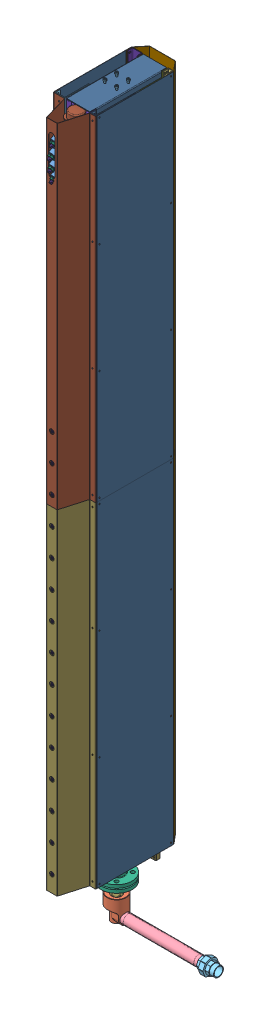
SolidWorks assembly Water Spray Pipe Assembly, configuration Default. Lengths in mm.
Overall size (606.2 3539.3 566.85).
223 component instances, 49 part files, 41 mates.
Components (placement in the parent):
- PPR Water Splitter Assembly – Union Type-1: PPR Water Splitter Assembly – Union Type [Default] at (0 1706.7846 0) x (0 0 1) z (-1 0 0) size (560.85 3301.11 212.13)
  - solenoid_valve_sc_g238c020_3b_oh-1: solenoid_valve_sc_g238c020_3b_oh [Default] at (52.5 414 0) x (-1 0 0) z (0 0 -1) size (140 159.5 110)
    - solenoid_valve_1b_3b_oh-1: solenoid_valve_1b_3b_oh [Default] at origin size (140 159.5 110)
    - solenoid_valve_2b_3b_3b_oh-1: solenoid_valve_2b_3b_3b_oh [Default] at origin size (54 39 30)
    - solenoid_valve_3b_3b_3b_oh-1: solenoid_valve_3b_3b_3b_oh [Default] at (0 212 0) x (1 0 0) z (0 0 -1) size (37.4 51.76 29.51)
  - DN40 Stainless-Steel Water Distributor Assembly-1: DN40 Stainless-Steel Water Distributor Assembly [Default] at origin size (334.07 3215.43 212.13)
    - DN50 PPR water distribution pipe-1: DN50 PPR water distribution pipe [Default] at origin size (244 3175 50)
    - DN50 PPR male-thread union-2: DN50 PPR male-thread union [Default] at (-110.1859 414 0) x (1 0 0) z (0 0.815822 -0.578303) size (73 95.5 95.5)
    - DN50 PPR male-thread union-3: DN50 PPR male-thread union [Default] at (-110.1859 1074 0) x (1 0 0) z (0 0.815822 -0.578303) size (73 95.5 95.5)
    - DN50 PPR male-thread union-4: DN50 PPR male-thread union [Default] at (-110.1859 1734 0) x (1 0 0) z (0 0.815822 -0.578303) size (73 95.5 95.5)
    - DN40-PN25 threaded flange-1: DN40-PN25 threaded flange [Default] at (0 -15 0) x (0 1 0) z (0.707107 0 0.707107) size (34 150 150)
    - DN50 PPR tee-1: DN50 PPR tee [Default] at (-194 414 0) size (85.5 103 68)
    - DN50 PPR female-thread straight connector-1: DN50 PPR female-thread straight connector [Default] at (-142.5 216 0) x (1 0 0) z (0 0.920901 -0.389797) size (67 79.98 79.98)
    - DN50 PPR elbow-1: DN50 PPR elbow [Default] at (-169 241 0) size (85.5 85.5 68)
    - DN50 PPR tee-2: DN50 PPR tee [Default] at (-194 1074 0) size (85.5 103 68)
    - DN50 PPR tee-3: DN50 PPR tee [Default] at (-194 1734 0) size (85.5 103 68)
    - DN50 PPR elbow-2: DN50 PPR elbow [Default] at (-169 3125 0) x (1 0 0) z (0 0 -1) size (85.5 85.5 68)
    - DN50 PPR male-thread union-5: DN50 PPR male-thread union [Default] at (-110.1859 3150 0) x (1 0 0) z (0 0.057891 0.998323) size (73 95.5 95.5)
  - solenoid_valve_sc_g238c020_3b_oh-7: solenoid_valve_sc_g238c020_3b_oh [Default] at (52.5 1074 0) x (-1 0 0) z (0 0 -1) size (140 159.5 110)
    - solenoid_valve_1b_3b_oh-1: solenoid_valve_1b_3b_oh [Default] at origin size (140 159.5 110)
    - solenoid_valve_2b_3b_3b_oh-1: solenoid_valve_2b_3b_3b_oh [Default] at origin size (54 39 30)
    - solenoid_valve_3b_3b_3b_oh-1: solenoid_valve_3b_3b_3b_oh [Default] at (0 212 0) x (1 0 0) z (0 0 -1) size (37.4 51.76 29.51)
  - solenoid_valve_sc_g238c020_3b_oh-8: solenoid_valve_sc_g238c020_3b_oh [Default] at (52.5 1734 0) x (-1 0 0) z (0 0 -1) size (140 159.5 110)
    - solenoid_valve_1b_3b_oh-1: solenoid_valve_1b_3b_oh [Default] at origin size (140 159.5 110)
    - solenoid_valve_2b_3b_3b_oh-1: solenoid_valve_2b_3b_3b_oh [Default] at origin size (54 39 30)
    - solenoid_valve_3b_3b_3b_oh-1: solenoid_valve_3b_3b_3b_oh [Default] at (0 212 0) x (1 0 0) z (0 0 -1) size (37.4 51.76 29.51)
  - solenoid_valve_sc_g238c020_3b_oh-9: solenoid_valve_sc_g238c020_3b_oh [Default] at (52.5 3150 0) x (-1 0 0) z (0 0 -1) size (140 159.5 110)
    - solenoid_valve_1b_3b_oh-1: solenoid_valve_1b_3b_oh [Default] at origin size (140 159.5 110)
    - solenoid_valve_2b_3b_3b_oh-1: solenoid_valve_2b_3b_3b_oh [Default] at origin size (54 39 30)
    - solenoid_valve_3b_3b_3b_oh-1: solenoid_valve_3b_3b_3b_oh [Default] at (0 212 0) x (1 0 0) z (0 0 -1) size (37.4 51.76 29.51)
  - DN50 PPR Distribution Pipe Assembly-1: DN50 PPR Distribution Pipe Assembly [Default] at (194 414 0) x (-1 0 0) z (0 0 -1) size (278.5 642.21 108.73)
    - DN50 PPR tee-1: DN50 PPR tee [Default] at origin size (85.5 103 68)
    - DN50 PPR distributor pipe-1: DN50 PPR distributor pipe [Default] at origin size (50 620 50)
    - DN50 PPR end cap-1: DN50 PPR end cap [Default] at (0 289.2744 0) x (0.993444 0 0.114321) z (-0.114321 0 0.993444) size (66.6 34.61 66.6)
    - DN50 PPR end cap-2: DN50 PPR end cap [Default] at (0 -289.2744 0) x (-0.999521 0 0.030939) z (0.030939 0 0.999521) size (66.6 34.61 66.6)
    - PPR weld in saddle 50–20-1: PPR weld in saddle 50–20 [Default] at (0 132 0) x (0 1 0) z (0 0 1) size (32 32.84 32)
    - PPR weld in saddle 75–20-1: PPR weld in saddle 75–20 [Default] at (3.5 0 0) x (0 1 0) z (0 0 1) size (32 33.38 32)
    - PPR weld in saddle 50–20-5: PPR weld in saddle 50–20 [Default] at (0 264 0) x (0 1 0) z (0 0 1) size (32 32.84 32)
    - DN50 PPR coupling–distributor joint-1: DN50 PPR coupling–distributor joint [Default] at (69 0 0) x (0 0.790854 -0.612005) z (0 0.612005 0.790854) size (50 82 50)
    - DN50 PPR male-thread union-1: DN50 PPR male-thread union [Default] at (118.8141 0 0) x (1 0 0) z (0 -0.1498 -0.988716) size (73 95.5 95.5)
    - PPR weld in saddle 50–20-6: PPR weld in saddle 50–20 [Default] at (0 -264 0) x (0 -1 0) z (0 0 -1) size (32 32.84 32)
    - PPR weld in saddle 50–20-7: PPR weld in saddle 50–20 [Default] at (0 -132 0) x (0 -1 0) z (0 0 -1) size (32 32.84 32)
    - Female Thread Reducer DN15-DN8-1: Female Thread Reducer DN15-DN8 [Default] at (-107.5 -264 0) size (23.99 26.56 23)
    - PPR Female threaded coupling 20xDN15-1: PPR Female threaded coupling 20xDN15 [Default] at (-60.5 -264 0) x (-1 0 0) z (0 -0.051033 -0.998697) size (53.5 35 35)
    - Spay MEG 1530-1: Spay MEG 1530 [Default] at (-98.5 -264 0) x (0 0 1) z (0 -1 0) size (13.5 20.5 15.59)
    - Female Thread Reducer DN15-DN8-2: Female Thread Reducer DN15-DN8 [Default] at (-107.5 -132 0) size (23.99 26.56 23)
    - Female Thread Reducer DN15-DN8-4: Female Thread Reducer DN15-DN8 [Default] at (-107.5 132 0) size (23.99 26.56 23)
    - Female Thread Reducer DN15-DN8-5: Female Thread Reducer DN15-DN8 [Default] at (-107.5 264 0) size (23.99 26.56 23)
    - Spay MEG 1530-2: Spay MEG 1530 [Default] at (-98.5 -132 0) x (0 0 1) z (0 -1 0) size (13.5 20.5 15.59)
    - Spay MEG 1530-4: Spay MEG 1530 [Default] at (-98.5 132 0) x (0 0 1) z (0 -1 0) size (13.5 20.5 15.59)
    - Spay MEG 1530-5: Spay MEG 1530 [Default] at (-98.5 264 0) x (0 0 1) z (0 -1 0) size (13.5 20.5 15.59)
    - PPR Female threaded coupling 20xDN15-2: PPR Female threaded coupling 20xDN15 [Default] at (-60.5 -132 0) x (-1 0 0) z (0 -0.051033 -0.998697) size (53.5 35 35)
    - PPR Female threaded coupling 20xDN15-4: PPR Female threaded coupling 20xDN15 [Default] at (-60.5 132 0) x (-1 0 0) z (0 -0.051033 -0.998697) size (53.5 35 35)
    - PPR Female threaded coupling 20xDN15-5: PPR Female threaded coupling 20xDN15 [Default] at (-60.5 264 0) x (-1 0 0) z (0 -0.051033 -0.998697) size (53.5 35 35)
    - PPR Female threaded coupling 20xDN15-6: PPR Female threaded coupling 20xDN15 [Default] at (-60.5 0 0) x (-1 0 0) z (0 0.107959 -0.994155) size (53.5 35 35)
    - Female Thread Reducer DN15-DN8-6: Female Thread Reducer DN15-DN8 [Default] at (-107.5 0 0) size (23.99 26.56 23)
    - Spay MEG 1530-9: Spay MEG 1530 [Default] at (-98.5 0 0) x (0 0 1) z (0 -1 0) size (13.5 20.5 15.59)
  - DN50 PPR Distribution Pipe Assembly-2: DN50 PPR Distribution Pipe Assembly [Default] at (194 1074 0) x (-1 0 0) z (0 0 -1) size (278.5 642.21 108.73)
    - DN50 PPR tee-1: DN50 PPR tee [Default] at origin size (85.5 103 68)
    - DN50 PPR distributor pipe-1: DN50 PPR distributor pipe [Default] at origin size (50 620 50)
    - DN50 PPR end cap-1: DN50 PPR end cap [Default] at (0 289.2744 0) x (0.993444 0 0.114321) z (-0.114321 0 0.993444) size (66.6 34.61 66.6)
    - DN50 PPR end cap-2: DN50 PPR end cap [Default] at (0 -289.2744 0) x (-0.999521 0 0.030939) z (0.030939 0 0.999521) size (66.6 34.61 66.6)
    - PPR weld in saddle 50–20-1: PPR weld in saddle 50–20 [Default] at (0 132 0) x (0 1 0) z (0 0 1) size (32 32.84 32)
    - PPR weld in saddle 75–20-1: PPR weld in saddle 75–20 [Default] at (3.5 0 0) x (0 1 0) z (0 0 1) size (32 33.38 32)
    - PPR weld in saddle 50–20-5: PPR weld in saddle 50–20 [Default] at (0 264 0) x (0 1 0) z (0 0 1) size (32 32.84 32)
    - DN50 PPR coupling–distributor joint-1: DN50 PPR coupling–distributor joint [Default] at (69 0 0) x (0 0.790854 -0.612005) z (0 0.612005 0.790854) size (50 82 50)
    - DN50 PPR male-thread union-1: DN50 PPR male-thread union [Default] at (118.8141 0 0) x (1 0 0) z (0 -0.1498 -0.988716) size (73 95.5 95.5)
    - PPR weld in saddle 50–20-6: PPR weld in saddle 50–20 [Default] at (0 -264 0) x (0 -1 0) z (0 0 -1) size (32 32.84 32)
    - PPR weld in saddle 50–20-7: PPR weld in saddle 50–20 [Default] at (0 -132 0) x (0 -1 0) z (0 0 -1) size (32 32.84 32)
    - Female Thread Reducer DN15-DN8-1: Female Thread Reducer DN15-DN8 [Default] at (-107.5 -264 0) size (23.99 26.56 23)
    - PPR Female threaded coupling 20xDN15-1: PPR Female threaded coupling 20xDN15 [Default] at (-60.5 -264 0) x (-1 0 0) z (0 -0.051033 -0.998697) size (53.5 35 35)
    - Spay MEG 1530-1: Spay MEG 1530 [Default] at (-98.5 -264 0) x (0 0 1) z (0 -1 0) size (13.5 20.5 15.59)
    - Female Thread Reducer DN15-DN8-2: Female Thread Reducer DN15-DN8 [Default] at (-107.5 -132 0) size (23.99 26.56 23)
    - Female Thread Reducer DN15-DN8-4: Female Thread Reducer DN15-DN8 [Default] at (-107.5 132 0) size (23.99 26.56 23)
    - Female Thread Reducer DN15-DN8-5: Female Thread Reducer DN15-DN8 [Default] at (-107.5 264 0) size (23.99 26.56 23)
    - Spay MEG 1530-2: Spay MEG 1530 [Default] at (-98.5 -132 0) x (0 0 1) z (0 -1 0) size (13.5 20.5 15.59)
    - Spay MEG 1530-4: Spay MEG 1530 [Default] at (-98.5 132 0) x (0 0 1) z (0 -1 0) size (13.5 20.5 15.59)
    - Spay MEG 1530-5: Spay MEG 1530 [Default] at (-98.5 264 0) x (0 0 1) z (0 -1 0) size (13.5 20.5 15.59)
    - PPR Female threaded coupling 20xDN15-2: PPR Female threaded coupling 20xDN15 [Default] at (-60.5 -132 0) x (-1 0 0) z (0 -0.051033 -0.998697) size (53.5 35 35)
    - PPR Female threaded coupling 20xDN15-4: PPR Female threaded coupling 20xDN15 [Default] at (-60.5 132 0) x (-1 0 0) z (0 -0.051033 -0.998697) size (53.5 35 35)
    - PPR Female threaded coupling 20xDN15-5: PPR Female threaded coupling 20xDN15 [Default] at (-60.5 264 0) x (-1 0 0) z (0 -0.051033 -0.998697) size (53.5 35 35)
    - PPR Female threaded coupling 20xDN15-6: PPR Female threaded coupling 20xDN15 [Default] at (-60.5 0 0) x (-1 0 0) z (0 0.107959 -0.994155) size (53.5 35 35)
    - Female Thread Reducer DN15-DN8-6: Female Thread Reducer DN15-DN8 [Default] at (-107.5 0 0) size (23.99 26.56 23)
    - Spay MEG 1530-9: Spay MEG 1530 [Default] at (-98.5 0 0) x (0 0 1) z (0 -1 0) size (13.5 20.5 15.59)
  - DN50 PPR Distribution Pipe Assembly-3: DN50 PPR Distribution Pipe Assembly [Default] at (194 1734 0) x (-1 0 0) z (0 0 -1) size (278.5 642.21 108.73)
    - DN50 PPR tee-1: DN50 PPR tee [Default] at origin size (85.5 103 68)
    - DN50 PPR distributor pipe-1: DN50 PPR distributor pipe [Default] at origin size (50 620 50)
    - DN50 PPR end cap-1: DN50 PPR end cap [Default] at (0 289.2744 0) x (0.993444 0 0.114321) z (-0.114321 0 0.993444) size (66.6 34.61 66.6)
    - DN50 PPR end cap-2: DN50 PPR end cap [Default] at (0 -289.2744 0) x (-0.999521 0 0.030939) z (0.030939 0 0.999521) size (66.6 34.61 66.6)
    - PPR weld in saddle 50–20-1: PPR weld in saddle 50–20 [Default] at (0 132 0) x (0 1 0) z (0 0 1) size (32 32.84 32)
    - PPR weld in saddle 75–20-1: PPR weld in saddle 75–20 [Default] at (3.5 0 0) x (0 1 0) z (0 0 1) size (32 33.38 32)
    - PPR weld in saddle 50–20-5: PPR weld in saddle 50–20 [Default] at (0 264 0) x (0 1 0) z (0 0 1) size (32 32.84 32)
    - DN50 PPR coupling–distributor joint-1: DN50 PPR coupling–distributor joint [Default] at (69 0 0) x (0 0.790854 -0.612005) z (0 0.612005 0.790854) size (50 82 50)
    - DN50 PPR male-thread union-1: DN50 PPR male-thread union [Default] at (118.8141 0 0) x (1 0 0) z (0 -0.1498 -0.988716) size (73 95.5 95.5)
    - PPR weld in saddle 50–20-6: PPR weld in saddle 50–20 [Default] at (0 -264 0) x (0 -1 0) z (0 0 -1) size (32 32.84 32)
    - PPR weld in saddle 50–20-7: PPR weld in saddle 50–20 [Default] at (0 -132 0) x (0 -1 0) z (0 0 -1) size (32 32.84 32)
    - Female Thread Reducer DN15-DN8-1: Female Thread Reducer DN15-DN8 [Default] at (-107.5 -264 0) size (23.99 26.56 23)
    - PPR Female threaded coupling 20xDN15-1: PPR Female threaded coupling 20xDN15 [Default] at (-60.5 -264 0) x (-1 0 0) z (0 -0.051033 -0.998697) size (53.5 35 35)
    - Spay MEG 1530-1: Spay MEG 1530 [Default] at (-98.5 -264 0) x (0 0 1) z (0 -1 0) size (13.5 20.5 15.59)
    - Female Thread Reducer DN15-DN8-2: Female Thread Reducer DN15-DN8 [Default] at (-107.5 -132 0) size (23.99 26.56 23)
    - Female Thread Reducer DN15-DN8-4: Female Thread Reducer DN15-DN8 [Default] at (-107.5 132 0) size (23.99 26.56 23)
    - Female Thread Reducer DN15-DN8-5: Female Thread Reducer DN15-DN8 [Default] at (-107.5 264 0) size (23.99 26.56 23)
    - Spay MEG 1530-2: Spay MEG 1530 [Default] at (-98.5 -132 0) x (0 0 1) z (0 -1 0) size (13.5 20.5 15.59)
    - Spay MEG 1530-4: Spay MEG 1530 [Default] at (-98.5 132 0) x (0 0 1) z (0 -1 0) size (13.5 20.5 15.59)
    - Spay MEG 1530-5: Spay MEG 1530 [Default] at (-98.5 264 0) x (0 0 1) z (0 -1 0) size (13.5 20.5 15.59)
    - PPR Female threaded coupling 20xDN15-2: PPR Female threaded coupling 20xDN15 [Default] at (-60.5 -132 0) x (-1 0 0) z (0 -0.051033 -0.998697) size (53.5 35 35)
    - PPR Female threaded coupling 20xDN15-4: PPR Female threaded coupling 20xDN15 [Default] at (-60.5 132 0) x (-1 0 0) z (0 -0.051033 -0.998697) size (53.5 35 35)
    - PPR Female threaded coupling 20xDN15-5: PPR Female threaded coupling 20xDN15 [Default] at (-60.5 264 0) x (-1 0 0) z (0 -0.051033 -0.998697) size (53.5 35 35)
    - PPR Female threaded coupling 20xDN15-6: PPR Female threaded coupling 20xDN15 [Default] at (-60.5 0 0) x (-1 0 0) z (0 0.107959 -0.994155) size (53.5 35 35)
    - Female Thread Reducer DN15-DN8-6: Female Thread Reducer DN15-DN8 [Default] at (-107.5 0 0) size (23.99 26.56 23)
    - Spay MEG 1530-9: Spay MEG 1530 [Default] at (-98.5 0 0) x (0 0 1) z (0 -1 0) size (13.5 20.5 15.59)
  - DN50 PPR Distribution Pipe Assembly – Upper-1: DN50 PPR Distribution Pipe Assembly – Upper [Default] at (194 3150 0) x (-1 0 0) z (0 0 -1) size (298.35 272.21 108.73)
    - DN50 PPR tee-1: DN50 PPR tee [Default] at origin size (85.5 103 68)
    - upper DN50 PPR distributor-1: upper DN50 PPR distributor [Default] at origin size (50 250 50)
    - DN50 PPR end cap-1: DN50 PPR end cap [Default] at (0 104.2744 0) x (0.993444 0 0.114321) z (-0.114321 0 0.993444) size (66.6 34.61 66.6)
    - DN50 PPR end cap-2: DN50 PPR end cap [Default] at (0 -104.2744 0) x (-0.999521 0 0.030939) z (0.030939 0 0.999521) size (66.6 34.61 66.6)
    - PPR weld in saddle 50–20-1: PPR weld in saddle 50–20 [Default] at (0 75 0) x (0 1 0) z (0 0 1) size (32 32.84 32)
    - DN50 PPR coupling–distributor joint-1: DN50 PPR coupling–distributor joint [Default] at (69 0 0) x (0 0.790854 -0.612005) z (0 0.612005 0.790854) size (50 82 50)
    - DN50 PPR male-thread union-1: DN50 PPR male-thread union [Default] at (118.8141 0 0) x (1 0 0) z (0 -0.1498 -0.988716) size (73 95.5 95.5)
    - PPR weld in saddle 75–20-2: PPR weld in saddle 75–20 [Default] at (3.5 25 0) x (0 1 0) z (0 0 1) size (32 33.38 32)
    - PPR weld in saddle 50–20-8: PPR weld in saddle 50–20 [Default] at (0 -75 0) x (0 -1 0) z (0 0 -1) size (32 32.84 32)
    - PPR weld in saddle 75–20-3: PPR weld in saddle 75–20 [Default] at (3.5 -25 0) x (0 -1 0) z (0 0 -1) size (32 33.38 32)
    - PPR Female threaded coupling 20xDN15 45deg-1: PPR Female threaded coupling 20xDN15 45deg [Default] at (-74.4234 67.25 0) x (-0.866025 -0.5 0) z (0 0 -1) size (84.48 41.16 35)
    - Female Thread Reducer DN15-DN8-1: Female Thread Reducer DN15-DN8 [Default] at (-115.9926 43.25 0) x (0.866025 0.5 0) z (0 0 1) size (23.99 26.56 23)
    - Spay MEG 1530-1: Spay MEG 1530 [Default] at (-108.1984 47.75 0) x (0 0 -1) z (-0.5 0.866025 0) size (13.5 20.5 15.59)
    - PPR Female threaded coupling 20xDN15 45deg-3: PPR Female threaded coupling 20xDN15 45deg [Default] at (-83.4234 17.25 0) x (-0.866025 -0.5 0) z (0 0 -1) size (84.48 41.16 35)
    - Female Thread Reducer DN15-DN8-2: Female Thread Reducer DN15-DN8 [Default] at (-124.9926 -6.75 0) x (0.866025 0.5 0) z (0.112965 -0.195661 0.974143) size (23.99 26.56 23)
    - Spay MEG 1530-2: Spay MEG 1530 [Default] at (-117.1984 -2.25 0) x (0 0 -1) z (-0.5 0.866025 0) size (13.5 20.5 15.59)
    - PPR Female threaded coupling 20xDN15 45deg-4: PPR Female threaded coupling 20xDN15 45deg [Default] at (-83.4234 -32.75 0) x (-0.866025 -0.5 0) z (0 0 -1) size (84.48 41.16 35)
    - Female Thread Reducer DN15-DN8-3: Female Thread Reducer DN15-DN8 [Default] at (-124.9926 -56.75 0) x (0.866025 0.5 0) z (0.225773 -0.391051 0.892247) size (23.99 26.56 23)
    - Spay MEG 1530-3: Spay MEG 1530 [Default] at (-117.1984 -52.25 0) x (0 0 -1) z (-0.5 0.866025 0) size (13.5 20.5 15.59)
    - PPR Female threaded coupling 20xDN15 45deg-5: PPR Female threaded coupling 20xDN15 45deg [Default] at (-74.4234 -82.75 0) x (-0.866025 -0.5 0) z (0 0 -1) size (84.48 41.16 35)
    - Female Thread Reducer DN15-DN8-4: Female Thread Reducer DN15-DN8 [Default] at (-115.9926 -106.75 0) x (0.866025 0.5 0) z (0.316742 -0.548613 0.773756) size (23.99 26.56 23)
    - Spay MEG 1530-4: Spay MEG 1530 [Default] at (-108.1984 -102.25 0) x (0 0 -1) z (-0.5 0.866025 0) size (13.5 20.5 15.59)
- Rotary Flange Joint Assembly-1: Rotary Flange Joint Assembly [Default] at (0 1511.7846 0) x (0 0 -1) z (1 0 0) size (212.13 191.3 597.27)
  - HD40R bod-1: HD40R bod [Default] at (0 114 0) x (-1 0 0) z (0 0 1) size (91.8 116.07 91.8)
  - HD40R base v3-3b-1: HD40R base v3-3b [Default] at (0 109 0) x (0.931312 0 0.364223) z (-0.364223 0 0.931312) size (47.5 57 54.85)
  - DN40-PN25 threaded flange-1: DN40-PN25 threaded flange [Default] at (0 180 0) x (0 -1 0) z (-0.707107 0 0.707107) size (34 150 150)
  - water supply pipe-1: water supply pipe [Default] at (0 27.7 25.9) x (0 0 -1) z (0.848409 0.529341 0) size (400 48.3 48.3)
  - DN40 male-female thread adapter-2: DN40 male-female thread adapter [Default] at (0 27.7 413.2) x (0 0 1) z (0.026555 0.999647 0) size (78 76 76)
- Spray-Pipe Housing Assembly-1: Spray-Pipe Housing Assembly [Default] at (0 1777.7846 0) x (0 0 1) z (-1 0 0) size (418.83 3349 198)
  - spray-pipe housing – base-1: spray-pipe housing – base [Default] at origin size (370 25 120)
  - spray-pipe housing – rear panel-1: spray-pipe housing – rear panel [Default] at (0 3 0) x (-1 0 0) z (0 0 -1) size (28 3220 120)
  - spray-pipe housing – front panel-1: spray-pipe housing – front panel [Default] at (0 3 0) size (28 3220 120)
  - spray-pipe housing – cross bar-1: spray-pipe housing – cross bar [Default] at (0 660.5 0) size (314 25 120)
  - spray-pipe housing – cross bar-2: spray-pipe housing – cross bar [Default] at (0 1320.5 0) size (314 25 120)
  - spray-pipe housing – cross bar-3: spray-pipe housing – cross bar [Default] at (0 1980.5 0) size (314 25 120)
  - spray-pipe housing – cross bar-4: spray-pipe housing – cross bar [Default] at (0 2640.5 0) size (314 25 120)
  - spray-pipe housing – cover-1: spray-pipe housing – cover [Default] at (0 3223 0) size (370 25 120)
  - spray-pipe housing – pipe clamp-1: spray-pipe housing – pipe clamp [Default] at (194 451.5 0) size (63 20 90)
  - spray-pipe housing – pipe clamp-8: spray-pipe housing – pipe clamp [Default] at (194 234.5 0) x (1 0 0) z (0 0 -1) size (63 20 90)
  - spray-pipe housing – pipe clamp-9: spray-pipe housing – pipe clamp [Default] at (194 894.5 0) x (1 0 0) z (0 0 -1) size (63 20 90)
  - spray-pipe housing – pipe clamp-10: spray-pipe housing – pipe clamp [Default] at (194 1554.5 0) x (1 0 0) z (0 0 -1) size (63 20 90)
  - spray-pipe housing – pipe clamp-6: spray-pipe housing – pipe clamp [Default] at (194 1111.5 0) size (63 20 90)
  - spray-pipe housing – pipe clamp-7: spray-pipe housing – pipe clamp [Default] at (194 1771.5 0) size (63 20 90)
  - spray-pipe housing – pipe clamp-18: spray-pipe housing – pipe clamp [Default] at (194 2982.5 0) x (1 0 0) z (0 0 -1) size (63 20 90)
  - spray-pipe housing – pipe clamp-20: spray-pipe housing – pipe clamp [Default] at (194 3175.5 0) size (63 20 90)
  - Top flange-1: Top flange [Default] at (0 3226 0) x (0 0 -1) z (1 0 0) size (98 36 98)
  - foam-nozzle hose clamp-1: foam-nozzle hose clamp [Default] at (-163 -87 0) x (0 0 1) z (-1 0 0) size (58 120 21)
  - spray-pipe housing – main-nozzle locator-1: spray-pipe housing – main-nozzle locator [Default] at (0 53 0) size (314 3 120)
  - socket head cap screw_din-1: socket head cap screw_din [DIN 912 M8 x 20 --- 20N] at (28.2843 3244 28.2843) x (0 -1 0) z (0 0 1) size (28 13 13)
  - socket head cap screw_din-2: socket head cap screw_din [DIN 912 M8 x 20 --- 20N] at (28.2843 3244 -28.2843) x (0 -1 0) z (0 0 1) size (28 13 13)
  - socket head cap screw_din-3: socket head cap screw_din [DIN 912 M8 x 20 --- 20N] at (-28.2843 3244 28.2843) x (0 -1 0) z (0 0 1) size (28 13 13)
  - socket head cap screw_din-4: socket head cap screw_din [DIN 912 M8 x 20 --- 20N] at (-28.2843 3244 -28.2843) x (0 -1 0) z (0 0 1) size (28 13 13)
  - prevailing torque nut thin insert_din-1: prevailing torque nut thin insert_din [DIN EN ISO 10511 - M8 - N] at (28.2843 3219.3 -28.2843) x (1 0 0) z (0 -1 0) size (13 15.01 6.76)
  - prevailing torque nut thin insert_din-2: prevailing torque nut thin insert_din [DIN EN ISO 10511 - M8 - N] at (-28.2843 3219.3 -28.2843) x (1 0 0) z (0 -1 0) size (13 15.01 6.76)
  - prevailing torque nut thin insert_din-3: prevailing torque nut thin insert_din [DIN EN ISO 10511 - M8 - N] at (28.2843 3219.3 28.2843) x (1 0 0) z (0 -1 0) size (13 15.01 6.76)
  - prevailing torque nut thin insert_din-4: prevailing torque nut thin insert_din [DIN EN ISO 10511 - M8 - N] at (-28.2843 3219.3 28.2843) x (1 0 0) z (0 -1 0) size (13 15.01 6.76)
  - rear lower side cover-1: rear lower side cover [Default] at (-188 0 86.5) x (0 0 1) z (-1 0 0) size (50 1613 25)
  - rear upper side cover-1: rear upper side cover [Default] at (-188 1613 86.5) x (0 0 1) z (-1 0 0) size (50 1613 25)
  - front lower side cover - left-2: front lower side cover - left [Default] at (188 0 -74) x (0 0 1) z (-1 0 0) size (25 1613 25)
  - front upper side cover - left-2: front upper side cover - left [Default] at (188 1613 -74) x (0 0 1) z (-1 0 0) size (25 1613 25)
  - rear lower side cover - left-2: rear lower side cover - left [Default] at (-188 0 -74) x (0 0 1) z (-1 0 0) size (25 1613 25)
  - rear upper side cover - left-2: rear upper side cover - left [Default] at (-188 1613 -74) x (0 0 1) z (-1 0 0) size (25 1613 25)
  - front lower side cover-1: front lower side cover [Default] at (188 0 86.5) x (0 0 1) z (-1 0 0) size (50 1613 120)
  - front upper side cover-1: front upper side cover [Default] at (188 1613 86.5) x (0 0 1) z (-1 0 0) size (50 1613 120)
  - Foam Nozzle Cluster Assembly-1: Foam Nozzle Cluster Assembly [Default] at (56.5958 38.2308 85) x (0.866025 0.5 0) z (0 0 -1) size (162.22 74.5 56)
    - foam nozzle-1: foam nozzle [Default] at origin size (162.22 46 29)
    - foam-nozzle clamp-1: foam-nozzle clamp [Default] at (45.5 -35 -20.5) x (0 1 0) z (1 0 0) size (70 20 25)
    - foam-nozzle clamp-2: foam-nozzle clamp [Default] at (45.5 35 20.5) x (0 -1 0) z (1 0 0) size (70 20 25)
    - socket head cap screw_din-1: socket head cap screw_din [DIN 912 M6 x 50 --- 24N] at (45.5 30 29.5) x (0 0 -1) z (1 0 0) size (56 10 10)
    - socket head cap screw_din-2: socket head cap screw_din [DIN 912 M6 x 50 --- 24N] at (45.5 -30 29.5) x (0 0 -1) z (1 0 0) size (56 10 10)
    - prevailing torque nut thin insert_din-1: prevailing torque nut thin insert_din [DIN EN ISO 10511 - M6 - N] at (45.5 30 -23.4) x (0.923728 0.383049 0) z (0 0 -1) size (10 11.55 6)
    - prevailing torque nut thin insert_din-2: prevailing torque nut thin insert_din [DIN EN ISO 10511 - M6 - N] at (45.5 -30 -23.4) x (0.923728 0.383049 0) z (0 0 -1) size (10 11.55 6)
  - Foam Nozzle Cluster Assembly-2: Foam Nozzle Cluster Assembly [Default] at (35.5 1200 85) x (1 0 0) z (0 0 -1) size (162.22 74.5 56)
    - foam nozzle-1: foam nozzle [Default] at origin size (162.22 46 29)
    - foam-nozzle clamp-1: foam-nozzle clamp [Default] at (45.5 -35 -20.5) x (0 1 0) z (1 0 0) size (70 20 25)
    - foam-nozzle clamp-2: foam-nozzle clamp [Default] at (45.5 35 20.5) x (0 -1 0) z (1 0 0) size (70 20 25)
    - socket head cap screw_din-1: socket head cap screw_din [DIN 912 M6 x 50 --- 24N] at (45.5 30 29.5) x (0 0 -1) z (1 0 0) size (56 10 10)
    - socket head cap screw_din-2: socket head cap screw_din [DIN 912 M6 x 50 --- 24N] at (45.5 -30 29.5) x (0 0 -1) z (1 0 0) size (56 10 10)
    - prevailing torque nut thin insert_din-1: prevailing torque nut thin insert_din [DIN EN ISO 10511 - M6 - N] at (45.5 30 -23.4) x (0.923728 0.383049 0) z (0 0 -1) size (10 11.55 6)
    - prevailing torque nut thin insert_din-2: prevailing torque nut thin insert_din [DIN EN ISO 10511 - M6 - N] at (45.5 -30 -23.4) x (0.923728 0.383049 0) z (0 0 -1) size (10 11.55 6)
  - Foam Nozzle Cluster Assembly-3: Foam Nozzle Cluster Assembly [Default] at (35.5 1500 85) x (1 0 0) z (0 0 -1) size (162.22 74.5 56)
    - foam nozzle-1: foam nozzle [Default] at origin size (162.22 46 29)
    - foam-nozzle clamp-1: foam-nozzle clamp [Default] at (45.5 -35 -20.5) x (0 1 0) z (1 0 0) size (70 20 25)
    - foam-nozzle clamp-2: foam-nozzle clamp [Default] at (45.5 35 20.5) x (0 -1 0) z (1 0 0) size (70 20 25)
    - socket head cap screw_din-1: socket head cap screw_din [DIN 912 M6 x 50 --- 24N] at (45.5 30 29.5) x (0 0 -1) z (1 0 0) size (56 10 10)
    - socket head cap screw_din-2: socket head cap screw_din [DIN 912 M6 x 50 --- 24N] at (45.5 -30 29.5) x (0 0 -1) z (1 0 0) size (56 10 10)
    - prevailing torque nut thin insert_din-1: prevailing torque nut thin insert_din [DIN EN ISO 10511 - M6 - N] at (45.5 30 -23.4) x (0.923728 0.383049 0) z (0 0 -1) size (10 11.55 6)
    - prevailing torque nut thin insert_din-2: prevailing torque nut thin insert_din [DIN EN ISO 10511 - M6 - N] at (45.5 -30 -23.4) x (0.923728 0.383049 0) z (0 0 -1) size (10 11.55 6)
  - Foam Nozzle Cluster Assembly-4: Foam Nozzle Cluster Assembly [Default] at (83.145 3135.2468 85) x (0.766044 -0.642788 0) z (0 0 -1) size (162.22 74.5 56)
    - foam nozzle-1: foam nozzle [Default] at origin size (162.22 46 29)
    - foam-nozzle clamp-1: foam-nozzle clamp [Default] at (45.5 -35 -20.5) x (0 1 0) z (1 0 0) size (70 20 25)
    - foam-nozzle clamp-2: foam-nozzle clamp [Default] at (45.5 35 20.5) x (0 -1 0) z (1 0 0) size (70 20 25)
    - socket head cap screw_din-1: socket head cap screw_din [DIN 912 M6 x 50 --- 24N] at (45.5 30 29.5) x (0 0 -1) z (1 0 0) size (56 10 10)
    - socket head cap screw_din-2: socket head cap screw_din [DIN 912 M6 x 50 --- 24N] at (45.5 -30 29.5) x (0 0 -1) z (1 0 0) size (56 10 10)
    - prevailing torque nut thin insert_din-1: prevailing torque nut thin insert_din [DIN EN ISO 10511 - M6 - N] at (45.5 30 -23.4) x (0.923728 0.383049 0) z (0 0 -1) size (10 11.55 6)
    - prevailing torque nut thin insert_din-2: prevailing torque nut thin insert_din [DIN EN ISO 10511 - M6 - N] at (45.5 -30 -23.4) x (0.923728 0.383049 0) z (0 0 -1) size (10 11.55 6)
- U bold-1: U bold [Default] at (0 2250.7846 -196) x (-1 0 0) z (0 -1 0) size (67 75.5 11.55)
- U bold-8: U bold [Default] at (0 1990.7846 -196) x (-1 0 0) z (0 -1 0) size (67 75.5 11.55)
- U bold-9: U bold [Default] at (0 2650.7846 -196) x (-1 0 0) z (0 -1 0) size (67 75.5 11.55)
- U bold-10: U bold [Default] at (0 3310.7846 -196) x (-1 0 0) z (0 -1 0) size (67 75.5 11.55)
- U bold-6: U bold [Default] at (0 2910.7846 -196) x (-1 0 0) z (0 -1 0) size (67 75.5 11.55)
- U bold-7: U bold [Default] at (0 3570.7846 -196) x (-1 0 0) z (0 -1 0) size (67 75.5 11.55)
- U bold-11: U bold [Default] at (0 4796.7846 -196) x (-1 0 0) z (0 -1 0) size (67 75.5 11.55)
- water-spray pipe cover – rear-8: water-spray pipe cover – rear [Default] at (-12.5 1777.7846 -233) x (-1 0 0) z (0 0 -1) size (203 1613 74)
- water-spray pipe cover – rear-9: water-spray pipe cover – rear [Default] at (-12.5 3390.7846 -233) x (-1 0 0) z (0 0 -1) size (203 1613 74)
- water-spray pipe cover – side-15: water-spray pipe cover – side [Default] at (-114 2584.2846 0) x (0 0 1) z (-1 0 0) size (370 1613 1)
- water-spray pipe cover – side-17: water-spray pipe cover – side [Default] at (90 2584.2846 0) x (0 0 1) z (-1 0 0) size (370 1613 1)
- water-spray pipe cover – side-18: water-spray pipe cover – side [Default] at (90 4197.2846 0) x (0 0 1) z (-1 0 0) size (370 1613 1)
- water-spray pipe cover – front-upper (reversed)-1: water-spray pipe cover – front-upper (reversed) [Default] at (0 3390.7846 311.5) size (203 1613 150)
- water-spray pipe cover – front-lower (reversed)-4: water-spray pipe cover – front-lower (reversed) [Default] at (0 1777.7846 311.5) size (203 1613 150)
- water-spray pipe cover – side-19: water-spray pipe cover – side [Default] at (-114 4197.2846 0) x (0 0 1) z (-1 0 0) size (370 1613 1)
Mates (geometry in assembly coordinates):
- Coincident3: coincident aligned: line of PPR Water Splitter Assembly – Union Type-1 through (0 1706.7846 0) axis (0 1 0)
- Coincident6: coincident aligned: plane of PPR Water Splitter Assembly – Union Type-1 through (0 1706.7846 0) normal (-1 0 0); plane of Spray-Pipe Housing Assembly-1 through (0 1777.7846 0) normal (-1 0 0)
- Coincident9: coincident anti-aligned: plane of rap ong chia nuoc ppr - zacco-1/rap ong inox chia nuoc DN40-1/Mat bich DN40-PN25 ren-3b-1 through (0 1691.7846 0) normal (0 -1 0); plane of rap khop noi xoay mat bich - 3b-1/Mat bich DN40-PN25 ren-3b-1 through (0 1691.7846 0) normal (0 1 0)
- Concentric6: concentric anti-aligned: cylinder of rap ong chia nuoc ppr - zacco-1/rap ong inox chia nuoc DN40-1/Mat bich DN40-PN25 ren-3b-1 through (0 1709.7846 0) axis (0 -1 0) radius 75; cylinder of rap khop noi xoay mat bich - 3b-1/Mat bich DN40-PN25 ren-3b-1 through (0 1673.7846 0) axis (0 1 0) radius 75
- Coincident11: coincident aligned: line of PPR Water Splitter Assembly – Union Type-1 through (0 1706.7846 0) axis (0 1 0); line of Spray-Pipe Housing Assembly-1 through (0 1777.7846 0) axis (0 1 0)
- Concentric7: concentric anti-aligned: cone of rap ong chia nuoc ppr - zacco-1/rap ong inox chia nuoc DN40-1/ong chia nuoc DN50 PPR-1 through (0 2120.7846 -148.15) axis (0 0 1); cylinder of rap hop chua ong phun_vStorage-1/hop chua ong phun - mat sau-1 through (0 2120.7846 -156.999) axis (0 0 -1) radius 35
- Coincident16: coincident aligned: plane of Spray-Pipe Housing Assembly-1 through (0 1777.7846 0) normal (0 0 1); plane of assembly through (0 0 0) normal (0 0 1)
- Perpendicular1: perpendicular: plane of rap khop noi xoay mat bich - 3b-1 through (0 1511.7846 0) normal (1 0 0); plane of assembly through (0 0 0) normal (0 0 1)
- Concentric24: concentric aligned: cylinder of rap hop chua ong phun_vStorage-1/hop chua ong phun - mat sau-1 through (28.5 2250.7846 -156.999) axis (0 0 -1) radius 3; cylinder of U bold-1 through (28.5 2250.7846 -153.5) axis (0 0 -1) radius 3
- Coincident36: coincident anti-aligned: plane of rap hop chua ong phun_vStorage-1/hop chua ong phun - mat sau-1 through (57 5000.7846 -157) normal (0 0 1); plane of U bold-1 through (0 2250.7846 -157) normal (0 0 -1)
- Concentric25: concentric anti-aligned: cylinder of rap hop chua ong phun_vStorage-1/hop chua ong phun - mat sau-1 through (-28.5 2250.7846 -156.999) axis (0 0 -1) radius 3; cylinder of U bold-1 through (-28.5 2250.7846 -196) axis (0 0 1) radius 3
- Concentric26: concentric aligned: cylinder of rap hop chua ong phun_vStorage-1/hop chua ong phun - mat sau-1 through (28.5 1990.7846 -156.999) axis (0 0 -1) radius 3; cylinder of U bold-2 through (28.5 1990.7846 -153.5) axis (0 0 -1) radius 3
- Coincident37: coincident anti-aligned: plane of rap hop chua ong phun_vStorage-1/hop chua ong phun - mat sau-1 through (57 5000.7846 -157) normal (0 0 1); plane of U bold-2 through (0 1990.7846 -157) normal (0 0 -1)
- Concentric27: concentric anti-aligned: cylinder of rap hop chua ong phun_vStorage-1/hop chua ong phun - mat sau-1 through (-28.5 1990.7846 -156.999) axis (0 0 -1) radius 3; cylinder of U bold-2 through (-28.5 1990.7846 -196) axis (0 0 1) radius 3
- Concentric28: concentric aligned: cylinder of rap hop chua ong phun_vStorage-1/hop chua ong phun - mat sau-1 through (28.5 4796.7846 -156.999) axis (0 0 -1) radius 3; cylinder of U bold-8 through (28.5 4796.7846 -153.5) axis (0 0 -1) radius 3
- Coincident39: coincident anti-aligned: plane of rap hop chua ong phun_vStorage-1/hop chua ong phun - mat sau-1 through (57 5000.7846 -157) normal (0 0 1); plane of U bold-8 through (0 4796.7846 -157) normal (0 0 -1)
- Concentric29: concentric anti-aligned: cylinder of rap hop chua ong phun_vStorage-1/hop chua ong phun - mat sau-1 through (-28.5 4796.7846 -156.999) axis (0 0 -1) radius 3; cylinder of U bold-8 through (-28.5 4796.7846 -196) axis (0 0 1) radius 3
- Distance22: distance = 1.5 mm anti-aligned: plane of op che ong phun nuoc - truoc duoi v2 nguoc-4 through (-113 3390.7846 189.5) normal (1 0 0); plane of rap hop chua ong phun_vStorage-1/op hong duoi truoc_v3-1 through (-111.5 3390.7846 188) normal (-1 0 0)
- Distance23: distance = 1.5 mm anti-aligned: plane of rap hop chua ong phun_vStorage-1/op hong duoi truoc_v3-1 through (-61.5 3390.7846 188) normal (0 0 1); plane of op che ong phun nuoc - truoc duoi v2 nguoc-4 through (-60 3390.7846 189.5) normal (0 0 -1)
- Coincident86: coincident aligned: plane of rap hop chua ong phun_vStorage-1/op hong duoi truoc_v3-1 through (-66 1777.7846 183.5) normal (0 -1 0); plane of op che ong phun nuoc - truoc duoi v2 nguoc-4 through (-112 1777.7846 190.5) normal (0 -1 0)
- Coincident87: coincident aligned: plane of op che ong phun nuoc - truoc tren v2 nguoc-1 through (-60 5003.7846 190.5) normal (0 0 1); plane of op che ong phun nuoc - truoc duoi v2 nguoc-4 through (-60 3390.7846 190.5) normal (0 0 1)
- Coincident88: coincident aligned: plane of op che ong phun nuoc - truoc tren v2 nguoc-1 through (-114 5003.7846 189.5) normal (-1 0 0); plane of op che ong phun nuoc - truoc duoi v2 nguoc-4 through (-114 3390.7846 189.5) normal (-1 0 0)
- Coincident89: coincident anti-aligned: plane of op che ong phun nuoc - truoc tren v2 nguoc-1 through (-112 3390.7846 190.5) normal (0 -1 0); plane of op che ong phun nuoc - truoc duoi v2 nguoc-4 through (87 3390.7846 188.5) normal (0 1 0)
- Coincident90: coincident anti-aligned: plane of op che ong phun nuoc - hong-17 through (89 2584.2846 0) normal (-1 0 0); plane of op che ong phun nuoc - truoc duoi v2 nguoc-4 through (89 3390.7846 189.5) normal (1 0 0)
- Concentric65: concentric anti-aligned: cylinder of op che ong phun nuoc - hong-17 through (90.001 1790.7846 172.5) axis (-1 0 0) radius 3.25; cylinder of op che ong phun nuoc - truoc duoi v2 nguoc-4 through (-123.1924 1790.7846 172.5) axis (1 0 0) radius 3.25
- Concentric66: concentric anti-aligned: cylinder of op che ong phun nuoc - hong-17 through (90.001 2319.7846 172.5) axis (-1 0 0) radius 3.25; cylinder of op che ong phun nuoc - truoc duoi v2 nguoc-4 through (-123.1924 2319.7846 172.5) axis (1 0 0) radius 3.25
- Distance24: distance = 1.5 mm anti-aligned: plane of op che ong phun nuoc - sau v2-8 through (-113 3390.7846 -187) normal (1 0 0); plane of rap hop chua ong phun_vStorage-1/op hong duoi sau-1 through (-111.5 3390.7846 -188) normal (-1 0 0)
- Concentric67: concentric anti-aligned: cylinder of rap hop chua ong phun_vStorage-1/op hong duoi sau-1 through (-111.501 3377.7846 -172.5) axis (1 0 0) radius 4.5; cylinder of op che ong phun nuoc - sau v2-8 through (98.1924 3377.7846 -172.5) axis (-1 0 0) radius 3.25
- Concentric68: concentric anti-aligned: cylinder of rap hop chua ong phun_vStorage-1/op hong duoi sau-1 through (-111.501 2848.7846 -172.5) axis (1 0 0) radius 4.5; cylinder of op che ong phun nuoc - sau v2-8 through (98.1924 2848.7846 -172.5) axis (-1 0 0) radius 3.25
- Coincident92: coincident aligned: plane of op che ong phun nuoc - sau v2-8 through (50.1675 3390.7846 -233.6428) normal (0.766044 0 -0.642788); plane of op che ong phun nuoc - sau v2-9 through (50.1675 5003.7846 -233.6428) normal (0.766044 0 -0.642788)
- Coincident94: coincident anti-aligned: plane of op che ong phun nuoc - sau v2-8 through (89 3390.7846 -186.636) normal (0 1 0); plane of op che ong phun nuoc - sau v2-9 through (48.9351 3390.7846 -234) normal (0 -1 0)
- Coincident95: coincident aligned: plane of op che ong phun nuoc - sau v2-8 through (-75.1675 3390.7846 -233.6428) normal (-0.766044 0 -0.642788); plane of op che ong phun nuoc - sau v2-9 through (-75.1675 5003.7846 -233.6428) normal (-0.766044 0 -0.642788)
- Coincident96: coincident anti-aligned: plane of op che ong phun nuoc - hong-18 through (89 4197.2846 0) normal (-1 0 0); plane of op che ong phun nuoc - truoc tren v2 nguoc-1 through (89 5003.7846 189.5) normal (1 0 0)
- Concentric69: concentric aligned: circle of op che ong phun nuoc - hong-18; circle of op che ong phun nuoc - truoc tren v2 nguoc-1
- Concentric70: concentric anti-aligned: cylinder of op che ong phun nuoc - hong-18 through (90.001 3932.7846 172.5) axis (-1 0 0) radius 3.25; cylinder of op che ong phun nuoc - truoc tren v2 nguoc-1 through (-123.1924 3932.7846 172.5) axis (1 0 0) radius 3.25
- Coincident98: coincident anti-aligned: plane of op che ong phun nuoc - hong-15 through (-114 2584.2846 0) normal (1 0 0); plane of op che ong phun nuoc - truoc duoi v2 nguoc-4 through (-114 3390.7846 189.5) normal (-1 0 0)
- Concentric71: concentric anti-aligned: cylinder of op che ong phun nuoc - hong-15 through (-113.999 1790.7846 172.5) axis (-1 0 0) radius 3.25; cylinder of op che ong phun nuoc - truoc duoi v2 nguoc-4 through (-123.1924 1790.7846 172.5) axis (1 0 0) radius 3.25
- Concentric72: concentric anti-aligned: cylinder of op che ong phun nuoc - hong-15 through (-113.999 2319.7846 172.5) axis (-1 0 0) radius 3.25; cylinder of op che ong phun nuoc - truoc duoi v2 nguoc-4 through (-123.1924 2319.7846 172.5) axis (1 0 0) radius 3.25
- Coincident99: coincident anti-aligned: plane of op che ong phun nuoc - truoc duoi v2 nguoc-4 through (-114 3390.7846 189.5) normal (-1 0 0); plane of op che ong phun nuoc - hong-19 through (-114 4197.2846 0) normal (1 0 0)
- Concentric73: concentric anti-aligned: cylinder of op che ong phun nuoc - truoc tren v2 nguoc-1 through (-123.1924 3403.7846 172.5) axis (1 0 0) radius 3.25; cylinder of op che ong phun nuoc - hong-19 through (-113.999 3403.7846 172.5) axis (-1 0 0) radius 3.25
- Concentric74: concentric anti-aligned: cylinder of op che ong phun nuoc - truoc tren v2 nguoc-1 through (-123.1924 3932.7846 172.5) axis (1 0 0) radius 3.25; cylinder of op che ong phun nuoc - hong-19 through (-113.999 3932.7846 172.5) axis (-1 0 0) radius 3.25
